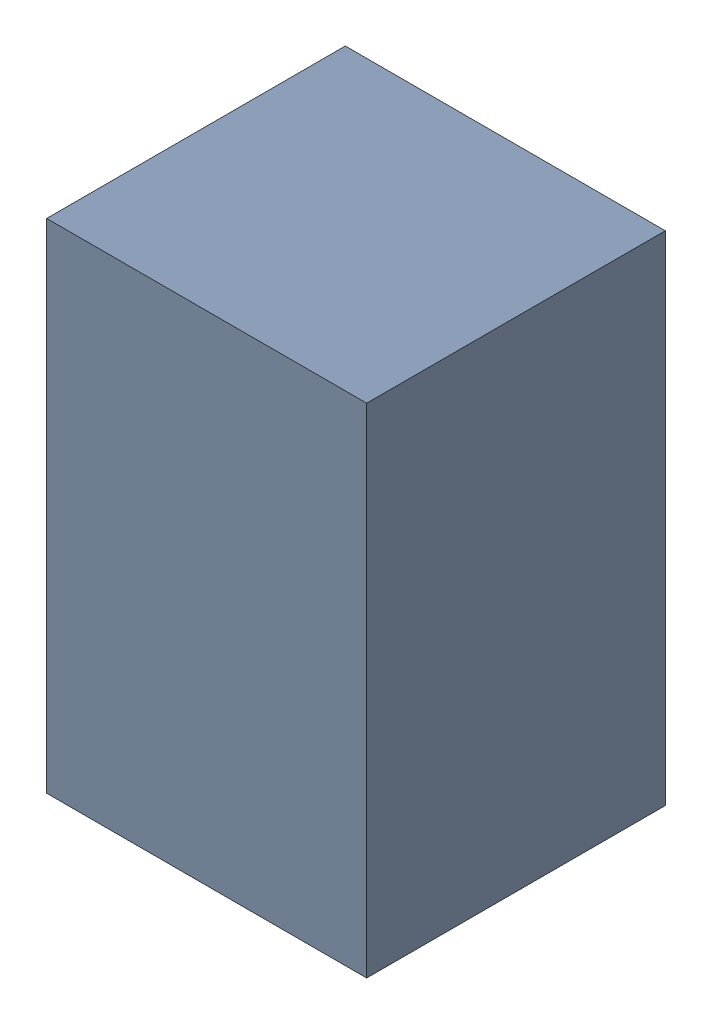
SolidWorks assembly C21, configuration Default. Lengths in mm.
Overall size (1.35 2.1 1.26).
2 component instances, 1 part files, 0 mates.
Components (placement in the parent):
- 407985696-1: 407985696 [Default] at (33.655 48.2476 0.0127) size (1.35 2.1 1.26)
  - Extruded_1-1: Extruded_1 [Default] at origin size (1.35 2.1 1.26)
